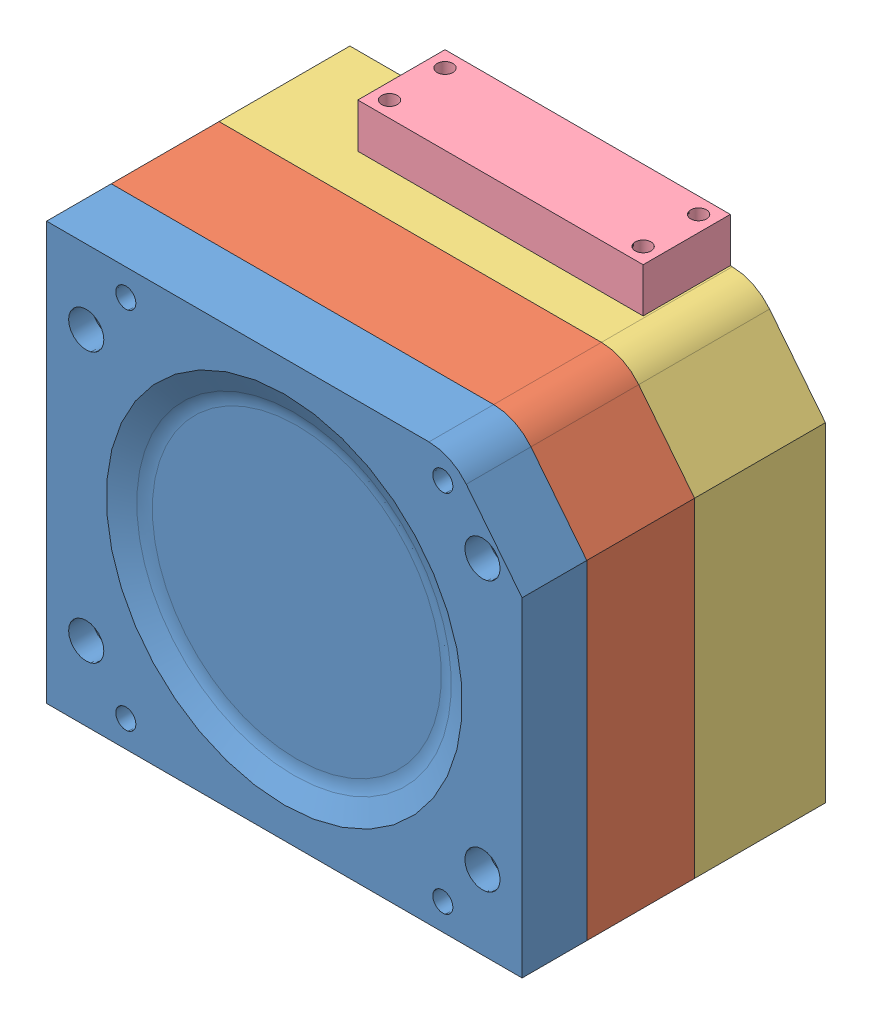
SolidWorks assembly Assem1, configuration Default. Lengths in mm.
Overall size (300 319.52 191.35).
5 component instances, 4 part files, 18 mates.
Components (placement in the parent):
- P_MOLD_SECTION_2-1: P_MOLD_SECTION_2 [Default] at (-94.1371 14.466 95.9581) size (300 263.53 40.81)
- P_MOLD_SECTION_3-1: P_MOLD_SECTION_3 [Default] at (-94.1371 14.466 95.9581) size (300 263.53 67.99)
- P_MOLD_SECTION_4-1: P_MOLD_SECTION_4 [Default] at (-94.1371 14.466 95.9581) size (300 273.93 82.55)
- P_MOLD_SECTION_5-3: P_MOLD_SECTION_5 [Default] at (-94.1371 14.466 95.9581) size (180 32.83 55)
- P_MOLD_SECTION_5-4: P_MOLD_SECTION_5 [Default] at (205.8629 277.991 95.9581) x (-1 0 0) z (0 0 1) size (180 32.83 55)
Mates (geometry in assembly coordinates):
- Coincident1: coincident: plane of P_MOLD_SECTION_2-1 through (-94.1371 14.466 287.3107) normal (0 0 1); plane of ? through (-94.1371 14.466 287.3107) normal (0 0 -1)
- Coincident2: coincident: plane of P_MOLD_SECTION_2-1 through (-94.1371 14.466 382.7236) normal (0 -1 0); plane of ? through (-94.1371 14.466 382.7236) normal (0 -1 0)
- Coincident3: coincident: plane of P_MOLD_SECTION_2-1 through (205.8629 14.466 382.7236) normal (1 0 0); plane of ? through (205.8629 14.466 382.7236) normal (1 0 0)
- Coincident4: coincident: plane of ? through (-94.1371 277.991 95.9581) normal (0 1 0); plane of ? through (205.8629 277.991 382.7236) normal (0 -1 0)
- Coincident5: coincident: plane of ? through (147.1161 247.991 382.7236) normal (0 0 1); plane of ? through (-35.3904 247.991 382.7236) normal (0 0 1)
- Concentric1: concentric: cylinder of ? through (55.8629 146.2285 321.3583) axis (0 0 1) radius 138.5553; cylinder of ? through (55.8629 146.2285 182.3234) axis (0 0 -1) radius 138.4275
- Coincident6: coincident: plane of P_MOLD_SECTION_2-1 through (-94.1371 14.466 246.5004) normal (0 0 -1); plane of P_MOLD_SECTION_3-1 through (-94.1371 14.466 246.5004) normal (0 0 1)
- Coincident7: coincident: plane of P_MOLD_SECTION_2-1 through (205.8629 14.466 382.7236) normal (1 0 0); plane of P_MOLD_SECTION_3-1 through (205.8629 14.466 382.7236) normal (1 0 0)
- Coincident8: coincident: plane of P_MOLD_SECTION_2-1 through (-94.1371 277.991 95.9581) normal (0 1 0); plane of P_MOLD_SECTION_3-1 through (-94.1371 277.991 95.9581) normal (0 1 0)
- Coincident9: coincident: plane of P_MOLD_SECTION_3-1 through (-94.1371 14.466 178.5081) normal (0 0 -1); plane of P_MOLD_SECTION_4-1 through (-94.1371 14.466 178.5081) normal (0 0 1)
- Coincident10: coincident: plane of P_MOLD_SECTION_3-1 through (-94.1371 277.991 382.7236) normal (-1 0 0); plane of P_MOLD_SECTION_4-1 through (-94.1371 277.991 382.7236) normal (-1 0 0)
- Coincident11: coincident: plane of P_MOLD_SECTION_3-1 through (-94.1371 14.466 382.7236) normal (0 -1 0); plane of P_MOLD_SECTION_4-1 through (-94.1371 14.466 382.7236) normal (0 -1 0)
- Coincident12: coincident: plane of P_MOLD_SECTION_4-1 through (-94.1371 14.466 382.7236) normal (0 -1 0); plane of P_MOLD_SECTION_5-4 through (205.8629 14.466 95.9581) normal (0 1 0)
- Coincident13: coincident: plane of P_MOLD_SECTION_4-1 through (147.1161 247.991 95.9581) normal (0 0 -1); plane of P_MOLD_SECTION_5-4 through (-35.3904 44.466 95.9581) normal (0 0 -1)
- Concentric2: concentric: cylinder of P_MOLD_SECTION_4-1 through (55.8629 146.2285 296.3583) axis (0 0 1) radius 138.4275; cylinder of P_MOLD_SECTION_5-4 through (55.8629 146.2285 296.3583) axis (0 0 1) radius 138.4275
- Coincident14: coincident: plane of P_MOLD_SECTION_4-1 through (-94.1371 277.991 95.9581) normal (0 1 0); plane of P_MOLD_SECTION_5-3 through (-94.1371 277.991 95.9581) normal (0 -1 0)
- Coincident15: coincident: plane of P_MOLD_SECTION_4-1 through (147.1161 247.991 95.9581) normal (0 0 -1); plane of P_MOLD_SECTION_5-3 through (147.1161 247.991 95.9581) normal (0 0 -1)
- Concentric3: concentric: cylinder of P_MOLD_SECTION_4-1 through (55.8629 146.2285 296.3583) axis (0 0 1) radius 138.4275; cylinder of P_MOLD_SECTION_5-3 through (55.8629 146.2285 296.3583) axis (0 0 1) radius 138.4275
